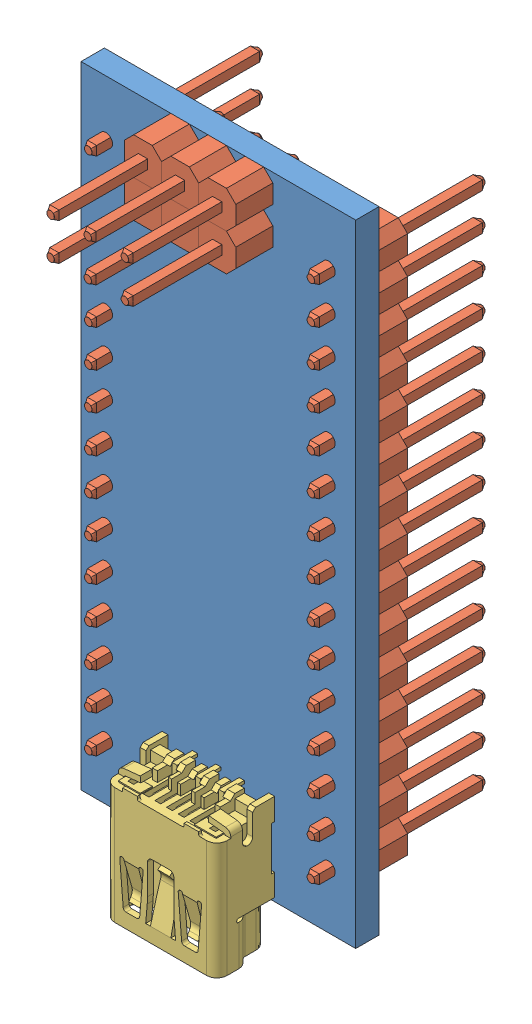
SolidWorks assembly Arduino Nano, configuration Default. Lengths in mm.
Overall size (18.8 45.93 19.41).
41 component instances, 3 part files, 12 mates.
Components (placement in the parent):
- arduino nano-1: arduino nano [Default] at origin size (18.8 43.18 1.6)
- Male Header 15 Pin-1: Male Header 15 Pin [Default] at (71.5511 -4.8683 -33.682) size (2.54 38.1 11.76)
  - Male Header Pin-1: Male Header Pin [Default] at (-69.8511 8.6783 31.142) size (2.54 2.54 11.76)
  - Male Header Pin-2: Male Header Pin [Default] at (-69.8511 11.2183 31.142) size (2.54 2.54 11.76)
  - Male Header Pin-3: Male Header Pin [Default] at (-69.8511 13.7583 31.142) size (2.54 2.54 11.76)
  - Male Header Pin-4: Male Header Pin [Default] at (-69.8511 16.2983 31.142) size (2.54 2.54 11.76)
  - Male Header Pin-5: Male Header Pin [Default] at (-69.8511 18.8383 31.142) size (2.54 2.54 11.76)
  - Male Header Pin-6: Male Header Pin [Default] at (-69.8511 21.3783 31.142) size (2.54 2.54 11.76)
  - Male Header Pin-7: Male Header Pin [Default] at (-69.8511 23.9183 31.142) size (2.54 2.54 11.76)
  - Male Header Pin-8: Male Header Pin [Default] at (-69.8511 26.4583 31.142) size (2.54 2.54 11.76)
  - Male Header Pin-9: Male Header Pin [Default] at (-69.8511 28.9983 31.142) size (2.54 2.54 11.76)
  - Male Header Pin-10: Male Header Pin [Default] at (-69.8511 31.5383 31.142) size (2.54 2.54 11.76)
  - Male Header Pin-11: Male Header Pin [Default] at (-69.8511 34.0783 31.142) size (2.54 2.54 11.76)
  - Male Header Pin-12: Male Header Pin [Default] at (-69.8511 36.6183 31.142) size (2.54 2.54 11.76)
  - Male Header Pin-13: Male Header Pin [Default] at (-69.8511 39.1583 31.142) size (2.54 2.54 11.76)
  - Male Header Pin-14: Male Header Pin [Default] at (-69.8511 41.6983 31.142) size (2.54 2.54 11.76)
  - Male Header Pin-15: Male Header Pin [Default] at (-69.8511 44.2383 31.142) size (2.54 2.54 11.76)
- Male Header 15 Pin-2: Male Header 15 Pin [Default] at (86.7911 -4.8683 -33.682) size (2.54 38.1 11.76)
  - Male Header Pin-1: Male Header Pin [Default] at (-69.8511 8.6783 31.142) size (2.54 2.54 11.76)
  - Male Header Pin-2: Male Header Pin [Default] at (-69.8511 11.2183 31.142) size (2.54 2.54 11.76)
  - Male Header Pin-3: Male Header Pin [Default] at (-69.8511 13.7583 31.142) size (2.54 2.54 11.76)
  - Male Header Pin-4: Male Header Pin [Default] at (-69.8511 16.2983 31.142) size (2.54 2.54 11.76)
  - Male Header Pin-5: Male Header Pin [Default] at (-69.8511 18.8383 31.142) size (2.54 2.54 11.76)
  - Male Header Pin-6: Male Header Pin [Default] at (-69.8511 21.3783 31.142) size (2.54 2.54 11.76)
  - Male Header Pin-7: Male Header Pin [Default] at (-69.8511 23.9183 31.142) size (2.54 2.54 11.76)
  - Male Header Pin-8: Male Header Pin [Default] at (-69.8511 26.4583 31.142) size (2.54 2.54 11.76)
  - Male Header Pin-9: Male Header Pin [Default] at (-69.8511 28.9983 31.142) size (2.54 2.54 11.76)
  - Male Header Pin-10: Male Header Pin [Default] at (-69.8511 31.5383 31.142) size (2.54 2.54 11.76)
  - Male Header Pin-11: Male Header Pin [Default] at (-69.8511 34.0783 31.142) size (2.54 2.54 11.76)
  - Male Header Pin-12: Male Header Pin [Default] at (-69.8511 36.6183 31.142) size (2.54 2.54 11.76)
  - Male Header Pin-13: Male Header Pin [Default] at (-69.8511 39.1583 31.142) size (2.54 2.54 11.76)
  - Male Header Pin-14: Male Header Pin [Default] at (-69.8511 41.6983 31.142) size (2.54 2.54 11.76)
  - Male Header Pin-15: Male Header Pin [Default] at (-69.8511 44.2383 31.142) size (2.54 2.54 11.76)
- Male Header 2x3 Pin-1: Male Header 2x3 Pin [Default] at (-54.6896 27.5359 31.7039) x (-1 0 0) z (0 0 -1) size (7.62 5.08 11.76)
  - Male Header Pin-1: Male Header Pin [Default] at (-66.5496 11.8341 27.5639) size (2.54 2.54 11.76)
  - Male Header Pin-2: Male Header Pin [Default] at (-64.0096 11.8341 27.5639) size (2.54 2.54 11.76)
  - Male Header Pin-3: Male Header Pin [Default] at (-61.4696 11.8341 27.5639) size (2.54 2.54 11.76)
  - Male Header Pin-4: Male Header Pin [Default] at (-66.5496 14.3741 27.5639) size (2.54 2.54 11.76)
  - Male Header Pin-5: Male Header Pin [Default] at (-64.0096 14.3741 27.5639) size (2.54 2.54 11.76)
  - Male Header Pin-6: Male Header Pin [Default] at (-61.4696 14.3741 27.5639) size (2.54 2.54 11.76)
- USB Mini-B Female-1: USB Mini-B Female [Default] at (9.4 -2.75 3.6) x (1 0 0) z (0 -1 0) size (7.7 5.76 9)
Mates (geometry in assembly coordinates):
- Coincident1: coincident anti-aligned: plane of arduino nano-1 through (0 43.18 0) normal (0 0 -1); plane of Male Header 15 Pin-1/Male Header Pin-1 through (2.97 5.08 0) normal (0 0 1)
- Concentric1: concentric anti-aligned: cylinder of arduino nano-1 through (1.7 3.81 1.6) axis (0 0 -1) radius 0.455; circle of Male Header 15 Pin-1/Male Header Pin-1
- Parallel5: parallel aligned: plane of arduino nano-1 through (0 43.18 1.6) normal (-1 0 0); plane of Male Header 15 Pin-1/Male Header Pin-1 through (0.43 3.175 0) normal (-1 0 0)
- Coincident9: coincident anti-aligned: plane of arduino nano-1 through (0 43.18 0) normal (0 0 -1); plane of Male Header 15 Pin-2/Male Header Pin-1 through (18.21 5.08 0) normal (0 0 1)
- Concentric2: concentric anti-aligned: cylinder of arduino nano-1 through (16.94 3.81 1.6) axis (0 0 -1) radius 0.455; circle of Male Header 15 Pin-2/Male Header Pin-1
- Parallel6: parallel aligned: plane of arduino nano-1 through (18.8 0 1.6) normal (1 0 0); plane of Male Header 15 Pin-2/Male Header Pin-1 through (18.21 3.175 0) normal (1 0 0)
- Coincident11: coincident anti-aligned: plane of arduino nano-1 through (0 43.18 1.6) normal (0 0 1); plane of Male Header 2x3 Pin-1/Male Header Pin-1 through (10.59 40.64 1.6) normal (0 0 -1)
- Concentric3: concentric aligned: cylinder of arduino nano-1 through (6.78 39.37 1.6) axis (0 0 -1) radius 0.455; circle of Male Header 2x3 Pin-1/Male Header Pin-3
- Parallel7: parallel aligned: plane of arduino nano-1 through (18.8 43.18 1.6) normal (0 1 0); plane of Male Header 2x3 Pin-1/Male Header Pin-6 through (7.415 43.18 1.6) normal (0 1 0)
- Coincident13: coincident anti-aligned: plane of arduino nano-1 through (0 43.18 1.6) normal (0 0 1); plane of USB Mini-B Female-1 through (13.25 0 1.6) normal (0 0 -1)
- Coincident14: coincident aligned: plane of arduino nano-1 through (0 0 1.6) normal (0 -1 0); plane of USB Mini-B Female-1 through (6.25 0 5.55) normal (0 -1 0)
- Width1: width anti-aligned: plane of USB Mini-B Female-1 through (13.25 -2.75 4.85) normal (1 0 0); plane of USB Mini-B Female-1 through (5.55 -2.75 4.0534) normal (-1 0 0); plane of arduino nano-1 through (0 43.18 1.6) normal (-1 0 0); plane of arduino nano-1 through (18.8 0 1.6) normal (1 0 0)
